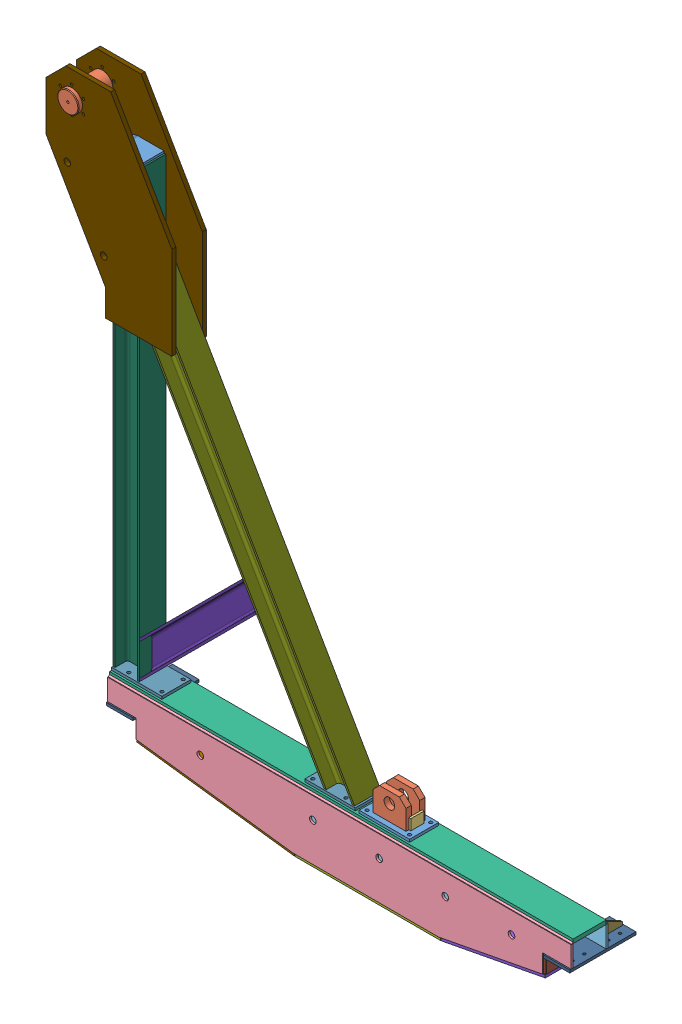
SolidWorks assembly Fahrwerk, configuration Standard. Lengths in mm.
Overall size (3975 4310 510).
71 component instances, 37 part files, 3 mates.
Components (placement in the parent):
- 110290-1: 110290 [Standard] at (310 255 -125) x (1 0 0) z (0 1 0) size (380 220 220)
  - 110291-1: 110291 [Standard] at origin size (380 220 20)
  - 110292-1: 110292 [Standard] at (0 -32 120) x (1 0 0) z (0 -1 0) size (250 200 40)
  - 110292-2: 110292 [Standard] at (0 72 120) x (1 0 0) z (0 -1 0) size (250 200 40)
  - 110293-1: 110293 [Standard] at (-140 0 60) x (0 1 0) z (1 0 0) size (100 80 15)
  - 110293-2: 110293 [Standard] at (140 0 60) x (0 -1 0) z (-1 0 0) size (100 80 15)
- 110210-1: 110210 [Standard] at origin size (3500 510 500)
  - 110211-1: 110211 [Standard] at origin size (3500 450 15)
  - 110220-1: 110220 [Standard] at (0 0 -265) size (3500 450 15)
  - 110212-1: 110212 [Standard] at (0 225 -125) x (1 0 0) z (0 1 0) size (3500 250 30)
  - 110213-1: 110213 [Standard] at (199.1883 -255 -125) x (1 0 0) z (0 1 0) size (1100 250 30)
  - 110214-1: 110214 [Standard] at (1147.7192 -179.4679 -125) x (0.982265 0.1875 0) z (-0.1875 0.982265 0) size (800 250 30)
  - 110215-1: 110215 [Standard] at (-949.8253 -179.3632 -125) x (0.992073 -0.125665 0) z (0.125665 0.992073 0) size (1200 250 30)
  - 110217-1: 110217 [Standard] at (1650 45 -225) x (0 0 1) z (0 1 0) size (500 200 20)
  - 110217-2: 110217 [Standard] at (-1650 45 -225) x (0 0 1) z (0 1 0) size (500 200 20)
  - 110218-1: 110218 [Standard] at (-1550 75 -125) x (0 -1 0) z (1 0 0) size (300 250 15)
  - 110219-1: 110219 [Standard] at (1642.5 115 -365) x (0 0 1) z (1 0 0) size (200 100 15)
  - 110218-2: 110218 [Standard] at (1550 75 -125) x (0 1 0) z (-1 0 0) size (300 250 15)
  - ISO 4032 M12-1: ISO 4032 M12 [Standard] at (700 -87 -239.2) x (0 0 -1) z (1 0 0) (suppressed, hidden)
  - ISO 4032 M12-2: ISO 4032 M12 [Standard] at (700 -167 -239.2) x (0 0 -1) z (1 0 0) (suppressed, hidden)
  - ISO 4032 M12-3: ISO 4032 M12 [Standard] at (800 -167 -239.2) x (0 0 -1) z (1 0 0) (suppressed, hidden)
  - ISO 4032 M12-4: ISO 4032 M12 [Standard] at (800 -87 -239.2) x (0 0 -1) z (1 0 0) (suppressed, hidden)
  - ISO 4032 M12-5: ISO 4032 M12 [Standard] at (-1400 185 -239.2) x (0 0 -1) z (1 0 0) (suppressed, hidden)
  - Sechskantmutter M20-1: Sechskantmutter M20 [Standard] at (-1400 207 -205) x (0 1 0) z (0 0 1) (suppressed, hidden)
  - Sechskantmutter M20-2: Sechskantmutter M20 [Standard] at (-260 207 -205) x (0 1 0) z (0 0 1) (suppressed, hidden)
  - Sechskantmutter M20-3: Sechskantmutter M20 [Standard] at (-260 225 -45) x (0 -1 0) z (0 0 -1) (suppressed, hidden)
  - Sechskantmutter M20-4: Sechskantmutter M20 [Standard] at (-1400 207 -45) x (0 1 0) z (0 0 1) (suppressed, hidden)
  - Sechskantmutter M20-5: Sechskantmutter M20 [Standard] at (150 207 -45) x (0 1 0) z (0 0 1) (suppressed, hidden)
  - Sechskantmutter M20-6: Sechskantmutter M20 [Standard] at (470 207 -45) x (0 1 0) z (0 0 1) (suppressed, hidden)
  - Sechskantmutter M20-7: Sechskantmutter M20 [Standard] at (470 207 -205) x (0 1 0) z (0 0 1) (suppressed, hidden)
  - Sechskantmutter M20-8: Sechskantmutter M20 [Standard] at (150 207 -205) x (0 1 0) z (0 0 1) (suppressed, hidden)
  - Sechskantmutter M20-9: Sechskantmutter M20 [Standard] at (-10 225 -205) x (0 -1 0) z (0 0 1) (suppressed, hidden)
  - Sechskantmutter M20-10: Sechskantmutter M20 [Standard] at (-10 225 -45) x (0 -1 0) z (0 0 1) (suppressed, hidden)
  - 110221-1: 110221 [Standard] at (510 0 -125) x (0 1 0) z (-1 0 0) size (450 250 10)
  - 110221-2: 110221 [Standard] at (30 0 -125) x (0 1 0) z (-1 0 0) size (450 250 10)
- 110250-1: 110250 [Standard] at (-1560 255 -125) x (1 0 0) z (0 1 0) size (2315 260 3880)
  - 110251-1: 110251 [Standard] at origin size (380 220 20)
  - 110252-1: 110252 [Standard] at (-90 0 3370) x (0 0 -1) z (-1 0 0) size (3350 200 200)
  - 110253-1: 110253 [Standard] at (-76.6025 0 2784.5826) x (0.5 0 -0.866025) z (0.866025 0 0.5) size (3250 200 200)
  - 110251-2: 110251 [Standard] at (1460 0 0) x (-1 0 0) z (0 0 1) size (380 220 20)
  - 110254-1: 110254 [Standard] at (858.5281 0 1009.9495) x (-0.707107 0 -0.707107) z (-0.707107 0 0.707107) size (1300 200 200)
  - 110255-1: 110255 [Standard] at (-190 -130 3050) x (1 0 0) z (0 1 0) size (950 1500 30)
  - 110255-2: 110255 [Standard] at (-190 100 3050) x (1 0 0) z (0 1 0) size (950 1500 30)
  - 110256-1: 110256 [Standard] at (-90 115 1798) x (0 0 -1) z (0 -1 0) (suppressed, hidden)
  - 110257-1: 110257 [Standard] at (-402.5 0 2910.5588) x (0 1 0) z (-0.866025 0 -0.5) size (200 839.39 598.21)
  - Sechskantmutter M16-1: Sechskantmutter M16 [Standard] at (-383.3975 -85.2 3650) x (0 -1 0) z (0 0 1) (suppressed, hidden)
  - Sechskantmutter M16-2: Sechskantmutter M16 [Standard] at (-383.3975 85.2 3650) x (0 1 0) z (0 0 1) (suppressed, hidden)
  - Sechskantmutter M16-3: Sechskantmutter M16 [Standard] at (-470 -85.2 3700) x (0 -1 0) z (-0.866025 0 0.5) (suppressed, hidden)
  - Sechskantmutter M16-4: Sechskantmutter M16 [Standard] at (-470 85.2 3700) x (0 1 0) z (-0.866025 0 0.5) (suppressed, hidden)
  - Sechskantmutter M16-5: Sechskantmutter M16 [Standard] at (-556.6025 -85.2 3650) x (0 -1 0) z (-0.866025 0 -0.5) (suppressed, hidden)
  - Sechskantmutter M16-6: Sechskantmutter M16 [Standard] at (-556.6025 85.2 3650) x (0 1 0) z (-0.866025 0 -0.5) (suppressed, hidden)
  - Sechskantmutter M16-7: Sechskantmutter M16 [Standard] at (-556.6025 -85.2 3550) x (0 -1 0) z (0 0 -1) (suppressed, hidden)
  - Sechskantmutter M16-8: Sechskantmutter M16 [Standard] at (-556.6025 85.2 3550) x (0 1 0) z (0 0 -1) (suppressed, hidden)
  - Sechskantmutter M16-9: Sechskantmutter M16 [Standard] at (-470 -85.2 3500) x (0 -1 0) z (0.866025 0 -0.5) (suppressed, hidden)
  - Sechskantmutter M16-10: Sechskantmutter M16 [Standard] at (-470 85.2 3500) x (0 1 0) z (0.866025 0 -0.5) (suppressed, hidden)
  - Sechskantmutter M16-11: Sechskantmutter M16 [Standard] at (-383.3975 -85.2 3550) x (0 -1 0) z (0.866025 0 0.5) (suppressed, hidden)
  - Sechskantmutter M16-12: Sechskantmutter M16 [Standard] at (-383.3975 85.2 3550) x (0 1 0) z (0.866025 0 0.5) (suppressed, hidden)
- Bolzen-1: Bolzen [Standard] at (-2030 3855 -285) x (1 0 0) z (0 -1 0) size (160.5 320 160.5)
- bead3-1: bead3 [Standard] at origin size (3500 10 10)
- bead4-1: bead4 [Standard] at origin size (3500 10 10)
- bead5-1: bead5 [Standard] at origin size (1184.44 159.92 10)
- bead6-2: bead6 [Standard] at origin size (1100 10 10)
- bead7-1: bead7 [Standard] at origin size (787.69 159.82 10)
- bead8-1: bead8 [Standard] at origin size (1184.44 159.92 10)
- bead9-1: bead9 [Standard] at origin size (1100 10 10)
- bead10-1: bead10 [Standard] at origin size (787.69 159.82 10)
- bead11-1: bead11 [Standard] at origin size (10 139.8 10)
- bead12-1: bead12 [Standard] at origin size (12.09 11.88 250)
- bead13-1: bead13 [Standard] at origin size (10 139.8 10)
- bead14-1: bead14 [Standard] at origin size (10 139.8 10)
- bead15-1: bead15 [Standard] at origin size (10 139.8 10)
Mates (geometry in assembly coordinates):
- Konzentrisch2: concentric anti-aligned: cylinder of 110250-1/110255-1 through (-2030 3855 5) axis (0 0 -1) radius 80.25; cylinder of Bolzen-1 through (-2030 3855 -285) axis (0 0 1) radius 80.25
- Breite1: width = 865.6833 mm: plane of 110250-1/110255-1 through (-1750 3305 5) normal (0 0 1); plane of 110250-1/110255-2 through (-1750 3305 -255) normal (0 0 -1); plane of Bolzen-1 through (-1954.75 3855 -285) normal (0 0 -1); plane of Bolzen-1 through (-2021.353 3855 35) normal (0 0 1)
- Achse2: unknown: cylinder of 110290-1/110292-1 through (310 395 -53) axis (0 0 -1) radius 40; unknown of 110210-1/110220-1; unknown of 110210-1/110212-1; unknown of ?; unknown of 110210-1/110212-1; unknown of 110210-1/110215-1; unknown of ?; unknown of ?; unknown of 110210-1/110213-1; unknown of 110210-1/110214-1; unknown of ?; unknown of 110210-1/110215-1; unknown of 110210-1/110220-1; unknown of 110210-1/110220-1; unknown of 110210-1/110213-1; unknown of 110210-1/110220-1; unknown of 110210-1/110214-1; unknown of 110210-1/110218-2; unknown of ?; unknown of 110210-1/110218-2; unknown of 110210-1/110214-1; unknown of 110210-1/110220-1; unknown of 110210-1/110218-2; unknown of 110210-1/110218-1; unknown of 110210-1/110220-1; unknown of ?; unknown of 110210-1/110218-1; unknown of ?; unknown of ?
